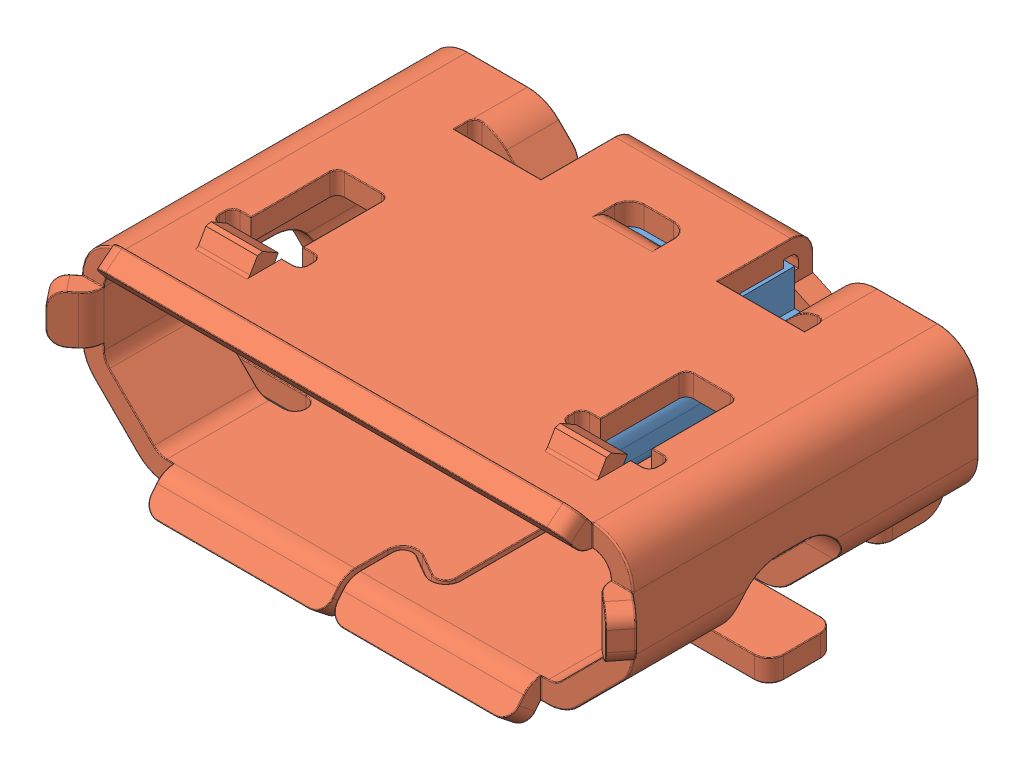
SolidWorks assembly micro USB, configuration Défaut. Lengths in mm.
Overall size (7.99 2.94 5.43).
2 component instances, 2 part files, 0 mates.
Components (placement in the parent):
- micro usb02-1: micro usb02 [Défaut] at (-14.4796 6.4719 -20.7085) size (6.9 2.16 4.2)
- micro usb-1: micro usb [Défaut] at (-14.4796 6.4719 -16.0085) size (7.99 2.94 5.43)
